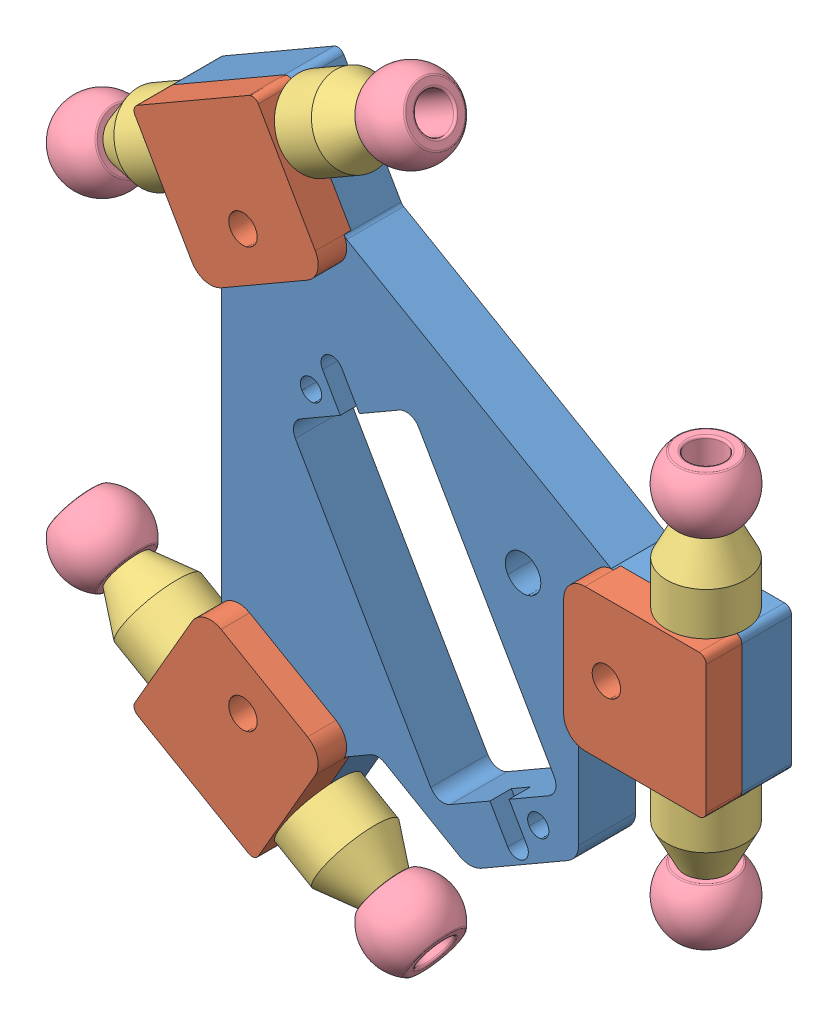
SolidWorks assembly End_Effector_Simscape, configuration Default. Lengths in mm.
Overall size (99.06 113.89 15.61).
16 component instances, 4 part files, 33 mates.
Components (placement in the parent):
- EndEffector_Simscape-1: EndEffector_Simscape [Default] at origin size (80.29 92.41 8)
- PartKhoaTruc-1: PartKhoaTruc [Default] at (38 0 7) x (0 1 0) z (0 0 1) size (20 20 5)
- PartKhoaTruc-2: PartKhoaTruc [Default] at (-19 32.909 7) x (-0.866025 -0.5 0) z (0 0 1) size (20 20 5)
- PartKhoaTruc-3: PartKhoaTruc [Default] at (-19 -32.909 7) x (0.866025 -0.5 0) z (0 0 1) size (20 20 5)
- Short Tru Nhua-1: Short Tru Nhua [Default] at (41.9824 10 6) size (11 11 11)
- Short Tru Nhua-2: Short Tru Nhua [Default] at (41.9824 -10 6) x (1 0 0) z (0 0 -1) size (11 11 11)
- Short Tru Nhua-3: Short Tru Nhua [Default] at (-29.7603 31.5463 6) x (0.041942 -0.072646 0.996475) z (0.498238 -0.862973 -0.083884) size (11 11 11)
- Short Tru Nhua-4: Short Tru Nhua [Default] at (-12.4397 41.5463 6) x (0.499772 -0.865631 0.030186) z (-0.015093 0.026142 0.999544) size (11 11 11)
- Short Tru Nhua-5: Short Tru Nhua [Default] at (-29.7603 -31.5463 6) x (0.5 0.866025 0) z (0 0 1) size (11 11 11)
- Short Tru Nhua-6: Short Tru Nhua [Default] at (-12.4397 -41.5463 6) x (-0.335104 -0.580417 -0.742173) z (-0.371087 -0.642741 0.670208) size (11 11 11)
- Ball Joint M5-11: Ball Joint M5 [Default] at (-42.749 -24.0472 6) x (0.497057 0.860929 -0.108333) z (0.054167 0.093819 0.994115) size (11.1 8 11.1)
- Ball Joint M5-10: Ball Joint M5 [Default] at (0.549 -49.0453 6) x (0.418761 0.725315 0.546404) z (-0.273202 -0.4732 0.837522) size (11.1 8 11.1)
- Ball Joint M5-8: Ball Joint M5 [Default] at (-42.749 24.0472 6) x (-0.497057 0.860929 -0.108333) z (-0.054167 0.093819 0.994115) size (11.1 8 11.1)
- Ball Joint M5-9: Ball Joint M5 [Default] at (0.549 49.0453 6) x (-0.498665 0.863712 0.073037) z (0.036519 -0.063252 0.997329) size (11.1 8 11.1)
- Ball Joint M5-7: Ball Joint M5 [Default] at (41.9824 24.9981 6) x (0.779743 0 -0.6261) z (0.6261 0 0.779743) size (11.1 8 11.1)
- Ball Joint M5-6: Ball Joint M5 [Default] at (41.9824 -24.9981 6) x (-0.556717 0 0.830702) z (-0.830702 0 -0.556717) size (11.1 8 11.1)
Mates (geometry in assembly coordinates):
- Coincident2: coincident anti-aligned: plane of EndEffector_Simscape-1 through (28 -7 7) normal (1 0 0); plane of PartKhoaTruc-1 through (28 -10 12) normal (-1 0 0)
- Coincident3: coincident aligned: plane of EndEffector_Simscape-1 through (30.6795 -10 8) normal (0 -1 0); plane of PartKhoaTruc-1 through (48 -10 12) normal (0 -1 0)
- Coincident4: coincident anti-aligned: plane of EndEffector_Simscape-1 through (31 7 7) normal (0 0 1); plane of PartKhoaTruc-1 through (38 0 7) normal (0 0 -1)
- Coincident5: coincident anti-aligned: plane of EndEffector_Simscape-1 through (-20.0622 20.7487 7) normal (-0.5 0.866025 0); plane of PartKhoaTruc-2 through (-5.3397 29.2487 12) normal (0.5 -0.866025 0)
- Coincident6: coincident anti-aligned: plane of EndEffector_Simscape-1 through (-9.4378 30.3468 7) normal (0 0 1); plane of PartKhoaTruc-2 through (-19 32.909 7) normal (0 0 -1)
- Coincident7: coincident aligned: plane of EndEffector_Simscape-1 through (-6.6795 31.5692 8) normal (0.866025 0.5 0); plane of PartKhoaTruc-2 through (-15.3397 46.5692 12) normal (0.866025 0.5 0)
- Coincident8: coincident anti-aligned: plane of EndEffector_Simscape-1 through (-7.9378 -27.7487 7) normal (-0.5 -0.866025 0); plane of PartKhoaTruc-3 through (-22.6603 -19.2487 12) normal (0.5 0.866025 0)
- Coincident9: coincident aligned: plane of EndEffector_Simscape-1 through (-6.6795 -31.5692 8) normal (0.866025 -0.5 0); plane of PartKhoaTruc-3 through (-15.3397 -46.5692 12) normal (0.866025 -0.5 0)
- Coincident10: coincident anti-aligned: plane of EndEffector_Simscape-1 through (-21.5622 -23.3468 7) normal (0 0 1); plane of PartKhoaTruc-3 through (-19 -32.909 7) normal (0 0 -1)
- Coincident11: coincident anti-aligned: axis of Short Tru Nhua-1 through (41.9824 16 6) axis (0 1 0)
- Coincident12: coincident anti-aligned: plane of PartKhoaTruc-1 through (48 10 12) normal (0 1 0); plane of Short Tru Nhua-1 through (46.9824 10 6) normal (0 -1 0)
- Coincident13: coincident anti-aligned: line of Short Tru Nhua-2 through (41.9824 -16 6) axis (0 1 0)
- Coincident14: coincident anti-aligned: plane of PartKhoaTruc-1 through (48 -10 12) normal (0 -1 0); plane of Short Tru Nhua-2 through (46.9824 -10 6) normal (0 1 0)
- Coincident15: coincident anti-aligned: line of Short Tru Nhua-4 through (-7.2436 44.5463 6) axis (-0.866025 -0.5 0)
- Coincident16: coincident anti-aligned: plane of PartKhoaTruc-2 through (-15.3397 46.5692 12) normal (0.866025 0.5 0); plane of Short Tru Nhua-4 through (-9.9409 37.2181 6.1509) normal (-0.866025 -0.5 0)
- Coincident17: coincident aligned: line of Short Tru Nhua-3 through (-34.9564 28.5463 6) axis (0.866025 0.5 0)
- Coincident18: coincident anti-aligned: plane of EndEffector_Simscape-1 through (-24 21.5692 8) normal (-0.866025 -0.5 0); plane of Short Tru Nhua-3 through (-29.5505 31.183 10.9824) normal (0.866025 0.5 0)
- Coincident19: coincident anti-aligned: line of Short Tru Nhua-6 through (-7.2436 -44.5463 6) axis (0.866025 -0.5 0)
- Coincident20: coincident anti-aligned: plane of EndEffector_Simscape-1 through (-6.6795 -31.5692 8) normal (0.866025 -0.5 0); plane of Short Tru Nhua-6 through (-14.1153 -44.4484 2.2891) normal (-0.866025 0.5 0)
- Coincident21: coincident anti-aligned: line of Short Tru Nhua-5 through (-34.9564 -28.5463 6) axis (0.866025 -0.5 0)
- Coincident22: coincident anti-aligned: plane of PartKhoaTruc-3 through (-32.6603 -36.5692 12) normal (-0.866025 0.5 0); plane of Short Tru Nhua-5 through (-27.2603 -27.2161 6) normal (0.866025 -0.5 0)
- Coincident23: coincident aligned: line of Ball Joint M5-8 through (-45.9516 22.1982 6) axis (0.866025 0.5 0)
- Coincident24: coincident anti-aligned: plane of Short Tru Nhua-3 through (-39.1607 25.8283 8.9894) normal (-0.866025 -0.5 0); plane of Ball Joint M5-8 through (-40.5292 28.1986 5.7292) normal (0.866025 0.5 0)
- Coincident25: coincident aligned: line of Ball Joint M5-9 through (-2.6537 47.1963 6) axis (0.866025 0.5 0)
- Coincident26: coincident anti-aligned: plane of Short Tru Nhua-4 through (-1.4142 44.4494 6.0906) normal (0.866025 0.5 0); plane of Ball Joint M5-9 through (-4.1601 49.2056 6.1826) normal (-0.866025 -0.5 0)
- Coincident27: coincident anti-aligned: line of Ball Joint M5-10 through (-2.6537 -47.1963 6) axis (0.866025 -0.5 0)
- Coincident28: coincident anti-aligned: plane of Short Tru Nhua-6 through (-3.9188 -48.7875 3.7735) normal (0.866025 -0.5 0); plane of Ball Joint M5-10 through (-1.8666 -45.233 7.366) normal (-0.866025 0.5 0)
- Coincident29: coincident anti-aligned: line of Ball Joint M5-11 through (-45.9516 -22.1982 6) axis (0.866025 -0.5 0)
- Coincident30: coincident anti-aligned: plane of Short Tru Nhua-5 through (-37.7865 -23.4482 6) normal (-0.866025 0.5 0); plane of Ball Joint M5-11 through (-38.0439 -23.894 5.7292) normal (0.866025 -0.5 0)
- Coincident31: coincident aligned: line of Ball Joint M5-6 through (41.9824 -21.3 6) axis (0 -1 0)
- Coincident32: coincident anti-aligned: plane of Short Tru Nhua-2 through (44.9824 -21 6) normal (0 -1 0); plane of Ball Joint M5-6 through (39.9795 -21 7.4961) normal (0 1 0)
- Coincident33: coincident aligned: line of Ball Joint M5-7 through (41.9824 52.1885 6) axis (0 -1 0)
- Coincident35: coincident anti-aligned: plane of Short Tru Nhua-1 through (44.9824 21 6) normal (0 1 0); plane of Ball Joint M5-7 through (43.9318 21 4.4348) normal (0 -1 0)
